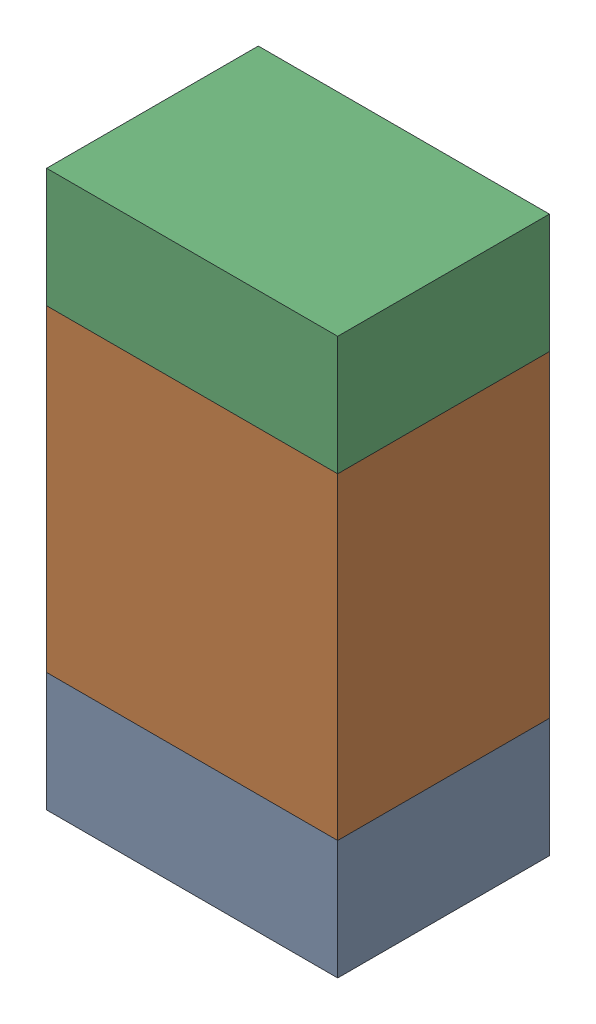
SolidWorks assembly R602_1PCB, configuration Default. Lengths in mm.
Overall size (0.55 1.05 0.4).
6 component instances, 2 part files, 0 mates.
Components (placement in the parent):
- 846483288-1: 846483288 [Default] at (105.8001 109.3876 -2.0638) size (0.55 0.22 0.4)
  - Extruded_12-1: Extruded_12 [Default] at origin size (0.55 0.22 0.4)
- 846483424-1: 846483424 [Default] at (105.8001 109.8001 -2.0638) size (0.55 0.6 0.4)
  - Extruded_13-1: Extruded_13 [Default] at origin size (0.55 0.6 0.4)
- 846483288-2: 846483288 [Default] at (105.8001 110.2126 -2.0638) size (0.55 0.22 0.4)
  - Extruded_12-1: Extruded_12 [Default] at origin size (0.55 0.22 0.4)
